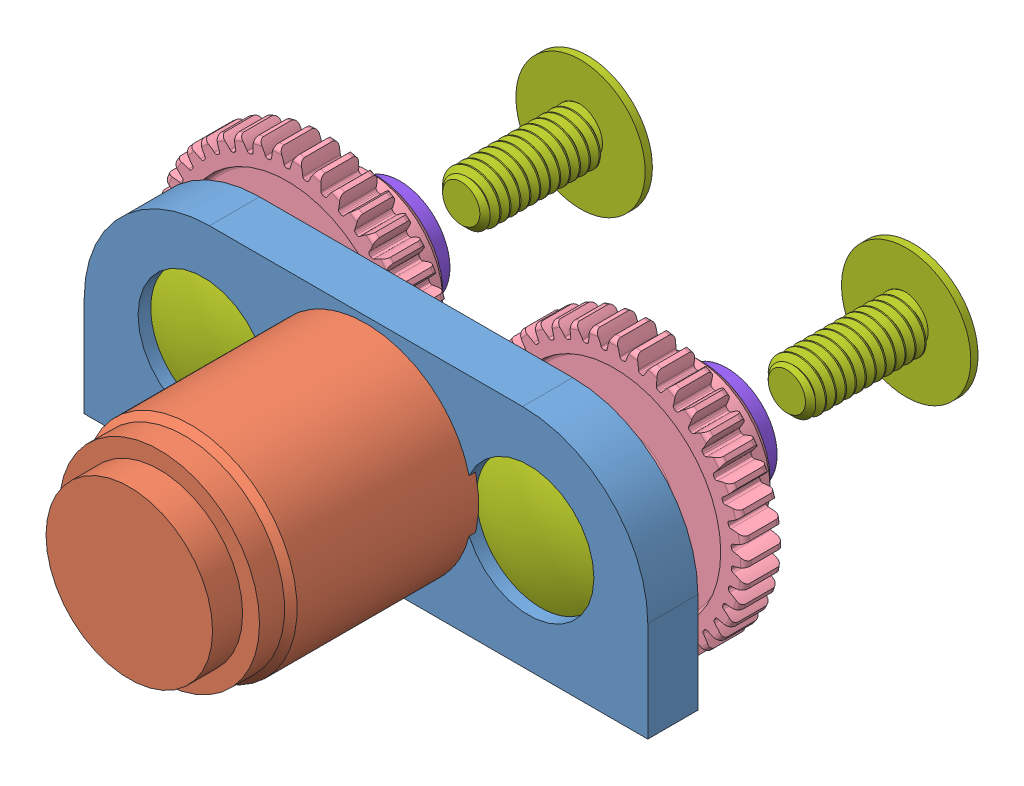
SolidWorks assembly motorassembly, configuration Default. Lengths in mm.
Overall size (55.17 29.38 50.59).
15 component instances, 8 part files, 30 mates.
Components (placement in the parent):
- smallmotormount-1: smallmotormount [Default] at (9.374 -3.21 4.9927) size (45 18 4)
- 1717SR-1: 1717SR [Default] at (-13.126 5.79 4.4927) size (17 17 28.5)
- 12g-1: 12g [Default] at (-13.126 5.79 -2.1073) x (0 0 1) z (-0.828983 0.559273 0) size (5.03 7.06 7.06)
- 40toothgearmod-1: 40toothgearmod [Default] at (-0.126 5.79 -3.3323) x (0 0 -1) z (0.582508 0.812825 0) size (7.03 21.05 21.05)
- 7804K104-1: 7804K104 [7804K104] at (-0.126 5.79 -3.2573) size (8 8 2.5)
- 7804K104-2: 7804K104 [7804K104] at (-0.126 5.79 -7.7073) size (8 8 2.5)
- 3mm spacer-1: 3mm spacer [93657A034] at (-0.126 5.79 -0.5073) x (0.468841 0.883283 0) z (0 0 1) size (8 8 3)
- 3mm spacer-2: 3mm spacer [93657A034] at (-26.126 5.79 -0.5073) size (8 8 3)
- 40toothgearmod-2: 40toothgearmod [Default] at (-26.126 5.79 -3.2073) x (0 0 -1) z (-0.852435 0.522834 0) size (7.03 21.05 21.05)
- 7804K104-3: 7804K104 [7804K104] at (-26.126 5.79 -7.4573) x (0.989675 -0.143329 0) z (0 0 1) size (8 8 2.5)
- 7804K104-4: 7804K104 [7804K104] at (-26.126 5.79 -3.5573) size (8 8 2.5)
- 93121A335-5: 93121A335 [93121A335] at (-26.126 5.79 -15.6123) x (0 0 -1) z (1 0 0) size (31.72 10.32 10.32)
- 93121A335-6: 93121A335 [93121A335] at (-0.126 5.79 -15.6123) x (0 0 -1) z (1 0 0) size (31.72 10.32 10.32)
- 2mm spacer-4: 2mm spacer [93657A031] at (-26.126 5.79 -9.7073) size (8 8 2)
- 2mm spacer-5: 2mm spacer [93657A031] at (-0.126 5.79 -9.8323) x (0.998742 -0.050146 0) z (0 0 1) size (8 8 2)
Mates (geometry in assembly coordinates):
- Coincident1: coincident anti-aligned: circle of smallmotormount-1; circle of 1717SR-1
- Coincident2: coincident anti-aligned: circle of smallmotormount-1; circle of 1717SR-1
- Concentric5: concentric aligned: cylinder of 1717SR-1 through (-13.126 5.79 -4.6073) axis (0 0 1) radius 0.75; cylinder of 12g-1 through (-13.126 5.79 -0.3073) axis (0 0 1) radius 1
- Concentric10: concentric anti-aligned: cylinder of 40toothgearmod-1 through (-0.126 5.79 -1.8035) axis (0 0 -1) radius 4; cylinder of 7804K104-1 through (-0.126 5.79 -2.0073) axis (0 0 1) radius 4
- Coincident13: coincident aligned: circle of 40toothgearmod-1; circle of 7804K104-1
- Concentric11: concentric anti-aligned: cylinder of 40toothgearmod-1 through (-0.126 5.79 -1.8035) axis (0 0 -1) radius 4; cylinder of 7804K104-2 through (-0.126 5.79 -6.4573) axis (0 0 1) radius 4
- Coincident14: coincident anti-aligned: circle of 40toothgearmod-1; circle of 7804K104-2
- Coincident18: coincident anti-aligned: plane of 1717SR-1 through (-13.126 5.79 1.3927) normal (0 0 -1); plane of 12g-1 through (-13.126 5.79 1.3927) normal (0 0 1)
- Coincident23: coincident anti-aligned: plane of smallmotormount-1 through (9.374 14.79 0.9927) normal (0 0 -1); plane of 3mm spacer-1 through (-0.126 5.79 0.9927) normal (0 0 1)
- Coincident24: coincident anti-aligned: plane of 7804K104-1 through (-0.126 9.665 -2.0073) normal (0 0 1); plane of 3mm spacer-1 through (-0.126 5.79 -2.0073) normal (0 0 -1)
- Coincident26: coincident anti-aligned: plane of smallmotormount-1 through (9.374 14.79 0.9927) normal (0 0 -1); plane of 3mm spacer-2 through (-26.126 5.79 0.9927) normal (0 0 1)
- Coincident27: coincident anti-aligned: plane of 3mm spacer-2 through (-26.126 5.79 -2.0073) normal (0 0 -1); circle of 40toothgearmod-2
- Concentric22: concentric anti-aligned: cylinder of 40toothgearmod-2 through (-26.126 5.79 -1.6785) axis (0 0 -1) radius 4; cylinder of 7804K104-4 through (-26.126 5.79 -2.3073) axis (0 0 1) radius 4
- Concentric23: concentric aligned: circle of 40toothgearmod-2; circle of 7804K104-4
- Coincident28: coincident aligned: plane of 40toothgearmod-2 through (-26.126 5.79 -2.3073) normal (0 0 1); plane of 7804K104-4 through (-26.126 8.7983 -2.3073) normal (0 0 1)
- Concentric24: concentric anti-aligned: cylinder of 40toothgearmod-2 through (-26.126 5.79 -1.6785) axis (0 0 -1) radius 4; cylinder of 7804K104-3 through (-26.126 5.79 -6.2073) axis (0 0 1) radius 4
- Coincident30: coincident aligned: plane of 40toothgearmod-2 through (-26.126 5.79 -8.7073) normal (0 0 -1); plane of 7804K104-3 through (-25.7497 8.3879 -8.7073) normal (0 0 -1)
- Coincident31: coincident anti-aligned: plane of smallmotormount-1 through (-26.126 5.79 3.4377) normal (0 0 1); plane of 93121A335-5 through (-26.126 5.79 3.4377) normal (0 0 -1)
- Concentric26: concentric anti-aligned: cylinder of smallmotormount-1 through (-26.126 5.79 0.9927) axis (0 0 1) radius 2.5; cylinder of 93121A335-5 through (-26.126 5.79 0.2627) axis (0 0 -1) radius 2.5797
- Concentric27: concentric aligned: cylinder of 3mm spacer-2 through (-26.126 5.79 0.9927) axis (0 0 -1) radius 2.65; cylinder of 93121A335-5 through (-26.126 5.79 0.2627) axis (0 0 -1) radius 2.5797
- Concentric28: concentric anti-aligned: cylinder of 7804K104-4 through (-26.126 5.79 -2.3073) axis (0 0 1) radius 2.5; cylinder of 93121A335-5 through (-26.126 5.79 0.2627) axis (0 0 -1) radius 2.5797
- Coincident35: coincident anti-aligned: plane of smallmotormount-1 through (-0.126 5.79 3.4377) normal (0 0 1); plane of 93121A335-6 through (-0.126 5.79 3.4377) normal (0 0 -1)
- Concentric33: concentric aligned: cylinder of 3mm spacer-1 through (-0.126 5.79 0.9927) axis (0 0 -1) radius 2.65; cylinder of 93121A335-6 through (-0.126 5.79 0.2627) axis (0 0 -1) radius 2.5797
- Concentric34: concentric anti-aligned: cylinder of smallmotormount-1 through (-0.126 5.79 0.9927) axis (0 0 1) radius 2.5; cylinder of 93121A335-6 through (-0.126 5.79 0.2627) axis (0 0 -1) radius 2.5797
- Coincident36: coincident anti-aligned: plane of 7804K104-1 through (-0.126 8.7983 -2.0073) normal (0 0 1); plane of 3mm spacer-1 through (-0.126 5.79 -2.0073) normal (0 0 -1)
- Concentric35: concentric anti-aligned: cylinder of 7804K104-1 through (-0.126 5.79 -2.0073) axis (0 0 1) radius 2.5; cylinder of 93121A335-6 through (-0.126 5.79 0.2627) axis (0 0 -1) radius 2.5797
- Concentric36: concentric anti-aligned: circle of 93121A335-6; circle of 2mm spacer-5
- Concentric37: concentric anti-aligned: circle of 93121A335-5; circle of 2mm spacer-4
- Coincident39: coincident anti-aligned: plane of 7804K104-3 through (-25.7497 8.3879 -8.7073) normal (0 0 -1); plane of 2mm spacer-4 through (-26.126 5.79 -8.7073) normal (0 0 1)
- Coincident41: coincident anti-aligned: plane of 40toothgearmod-1 through (-0.126 5.79 -8.8323) normal (0 0 -1); plane of 2mm spacer-5 through (-0.126 5.79 -8.8323) normal (0 0 1)
